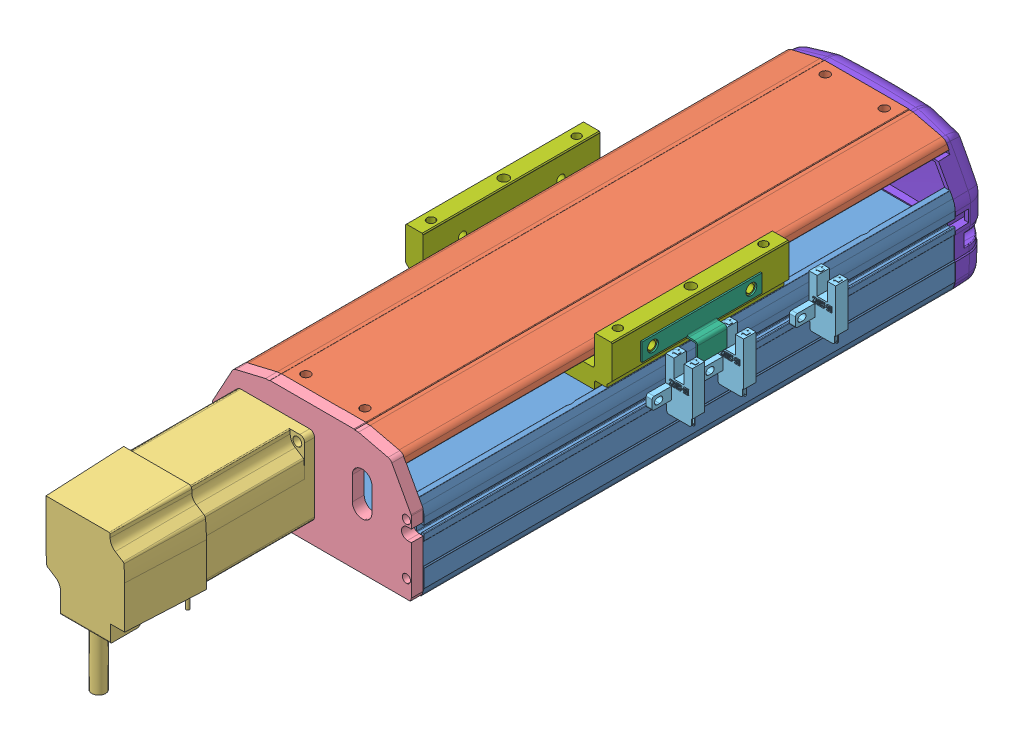
SolidWorks assembly S10-BC-100W, configuration 默认. Lengths in mm.
Overall size (117 93.4 393.51).
10 component instances, 8 part files, 32 mates.
Components (placement in the parent):
- S10-BC底座^S10-BC-100W-1: S10-BC底座^S10-BC-100W [默认] at origin size (102 43 282) (virtual)
- S10-BC上盖^S10-BC-100W-1: S10-BC上盖^S10-BC-100W [默认] at (0 59.5 144.1) size (83.88 8 276) (virtual)
-  M10^S10-BC-100W-1:  M10^S10-BC-100W [默认] at (-18.7 30.3 344) size (42.1 79.78 121.76) (virtual)
- S10-BC--P10电机板^S10-BC-100W-1: S10-BC--P10电机板^S10-BC-100W [Default] at (0 0 282) size (101 61.5 6) (virtual)
-  EE-SX672 传感器^S10-BC-100W-1:  EE-SX672 传感器^S10-BC-100W [默认] at (57.75 34.1 86.4) x (1 0 0) z (0 0 -1) size (13.5 27.4 26.1) (virtual)
- S10-GY外置感应钢片^S10-BC-100W-1: S10-GY外置感应钢片^S10-BC-100W [默认] at (52.9 60.5 143) size (6 19 61) (virtual)
-  EE-SX672 传感器^S10-BC-100W-2:  EE-SX672 传感器^S10-BC-100W [默认] at (57.75 34.1 133.1) x (1 0 0) z (0 0 -1) size (13.5 27.4 26.1) (virtual)
-  EE-SX672 传感器^S10-BC-100W-3:  EE-SX672 传感器^S10-BC-100W [默认] at (57.75 34.1 159.2) x (1 0 0) z (0 0 -1) size (13.5 27.4 26.1) (virtual)
- S10-BC滑座^S10-BC-100W-1: S10-BC滑座^S10-BC-100W [默认] at (-18.5 30.5 143) size (105 52.5 90) (virtual)
- S10端盖^S10-BC-100W-2: S10端盖^S10-BC-100W [默认] at (0.1 -1.5505 432.1) size (103.64 63.03 20.85) (virtual)
Mates (geometry in assembly coordinates):
- 重合23: coincident: plane of S10-BC底座^S10-BC-100W-1 through (-45.6042 41.8 282) normal (0 0 1); plane of S10-BC--P10电机板^S10-BC-100W-1 through (-37.9743 54.7457 282) normal (0 0 -1)
- 重合24: coincident: plane of S10-BC底座^S10-BC-100W-1 through (-24.5001 0 282) normal (0 -1 0); plane of S10-BC--P10电机板^S10-BC-100W-1 through (-49.9624 0 282) normal (0 -1 0)
- 重合25: coincident: plane of S10-BC底座^S10-BC-100W-1 through (-50.5 23.4167 282) normal (-1 0 0); plane of S10-BC--P10电机板^S10-BC-100W-1 through (-50.5 25.9995 282) normal (-1 0 0)
- 距离2: distance = 62.5 mm: plane of S10-BC上盖^S10-BC-100W-1 through (-21.3092 61.5 282.1) normal (0 1 0); plane of S10-BC底座^S10-BC-100W-1 through (0 -1 0) normal (0 -1 0)
- 重合31: coincident: plane of S10-BC底座^S10-BC-100W-1 through (0 0 0) normal (1 0 0); plane of S10-BC上盖^S10-BC-100W-1 through (0 59.5 144.1) normal (1 0 0)
- 距离3: distance = 66 mm: plane of S10-BC滑座^S10-BC-100W-1 through (-70.1396 65 72.2427) normal (0 1 0); plane of S10-BC底座^S10-BC-100W-1 through (0 -1 0) normal (0 -1 0)
- 距离5: distance = 1.5 mm: plane of S10-BC滑座^S10-BC-100W-1 through (52.5 45.0828 188) normal (1 0 0); plane of S10-BC底座^S10-BC-100W-1 through (51 3.0554 282) normal (1 0 0)
- 距离8: distance = 24 mm: plane of S10-BC底座^S10-BC-100W-1 through (0 -1 0) normal (0 -1 0); plane of  EE-SX672 传感器^S10-BC-100W-1 through (51 23 80.1) normal (0 -1 0)
- 重合59: coincident: plane of S10-BC底座^S10-BC-100W-1 through (51 24.0824 282) normal (1 0 0); plane of  EE-SX672 传感器^S10-BC-100W-1 through (51 45.2 80.1) normal (-1 0 0)
- 重合43: coincident: plane of S10-BC滑座^S10-BC-100W-1 through (52.5 45.0828 188) normal (1 0 0); plane of S10-GY外置感应钢片^S10-BC-100W-1 through (52.5 58.5 112.5) normal (-1 0 0)
- 重合51: coincident: plane of  EE-SX672 传感器^S10-BC-100W-1 through (51 45.2 80.1) normal (0 1 0); plane of  EE-SX672 传感器^S10-BC-100W-2 through (51 45.2 126.8) normal (0 1 0)
- 重合52: coincident: plane of  EE-SX672 传感器^S10-BC-100W-1 through (51 45.2 80.1) normal (0 1 0); plane of  EE-SX672 传感器^S10-BC-100W-3 through (51 45.2 152.9) normal (0 1 0)
- 重合56: coincident: plane of S10-BC--P10电机板^S10-BC-100W-1 through (-37.9743 54.7457 288) normal (0 0 1); plane of  M10^S10-BC-100W-1 through (59.2984 28.8022 288) normal (0 0 -1)
- 距离13: distance = 68 mm: plane of  EE-SX672 传感器^S10-BC-100W-1 through (64.5 23 80.1) normal (0 0 -1); plane of S10-BC底座^S10-BC-100W-1 through (46.75 42 12.1) normal (0 0 -1)
- 重合57: coincident: plane of  EE-SX672 传感器^S10-BC-100W-1 through (51 45.2 80.1) normal (-1 0 0); plane of  EE-SX672 传感器^S10-BC-100W-3 through (51 45.2 152.9) normal (-1 0 0)
- 重合58: coincident: plane of  EE-SX672 传感器^S10-BC-100W-2 through (51 45.2 126.8) normal (-1 0 0); plane of  EE-SX672 传感器^S10-BC-100W-3 through (51 45.2 152.9) normal (-1 0 0)
- 重合60: coincident: plane of  EE-SX672 传感器^S10-BC-100W-2 through (54 26.2 143) normal (0 0 1); plane of  EE-SX672 传感器^S10-BC-100W-3 through (54 26.2 143) normal (0 0 -1)
- 重合61: coincident: plane of S10-BC底座^S10-BC-100W-1 through (0 0 0) normal (1 0 0); plane of assembly through (0 0 0) normal (1 0 0)
- 重合62: coincident: plane of S10-BC底座^S10-BC-100W-1 through (0 0 0) normal (0 1 0); plane of assembly through (0 0 0) normal (0 1 0)
- 重合63: coincident: plane of S10-BC底座^S10-BC-100W-1 through (0 0 0) normal (0 0 1); plane of assembly through (0 0 0) normal (0 0 1)
- 重合65: coincident: plane of S10-BC底座^S10-BC-100W-1 through (46.75 42 12.1) normal (0 0 -1); plane of S10端盖^S10-BC-100W-2 through (-43.0846 34.4495 12.1) normal (0 0 1)
- 重合70: coincident: line of S10-BC底座^S10-BC-100W-1 through (47.4 31.8495 12.1) axis (1 0 0); line of S10端盖^S10-BC-100W-2 through (51.1 31.8495 12.1) axis (-1 0 0)
- 重合71: coincident: line of S10-BC底座^S10-BC-100W-1 through (47.1 26.4495 12.1) axis (0 1 0); line of S10端盖^S10-BC-100W-2 through (47.1 31.8495 12.1) axis (0 -1 0)
- 重合72: coincident: plane of S10-BC上盖^S10-BC-100W-1 through (-39.9297 53.7 6.1) normal (0 0 -1); plane of S10端盖^S10-BC-100W-2 through (50.1 51.9495 6.1) normal (0 0 1)
- 距离16: distance = 65.7 mm: cylinder of  M10^S10-BC-100W-1 through (-18.7 30.3 263) axis (0 0 1) radius 4; plane of S10-BC底座^S10-BC-100W-1 through (51 3.0554 282) normal (1 0 0)
- 距离17: distance = 27.3 mm: cylinder of  M10^S10-BC-100W-1 through (-18.7 30.3 263) axis (0 0 1) radius 4; plane of S10-BC底座^S10-BC-100W-1 through (0 -1 0) normal (0 -1 0)
- 平行2: parallel: plane of  M10^S10-BC-100W-1; plane of S10-BC--P10电机板^S10-BC-100W-1 through (-0.5 10 282) normal (0 1 0)
- 距离18: distance = 145 mm: plane of S10-BC--P10电机板^S10-BC-100W-1 through (-37.9743 54.7457 288) normal (0 0 1); cylinder of S10-BC滑座^S10-BC-100W-1 through (47.5 53 143) axis (0 1 0) radius 2.5
- 同心3: concentric: circle of S10-GY外置感应钢片^S10-BC-100W-1; cylinder of S10-BC滑座^S10-BC-100W-1 through (52.5 54 168) axis (1 0 0) radius 2.1
- 同心4: concentric: cylinder of S10-GY外置感应钢片^S10-BC-100W-1 through (52.5 54 118) axis (-1 0 0) radius 2.8; cylinder of S10-BC滑座^S10-BC-100W-1 through (52.5 54 118) axis (1 0 0) radius 2.1
- 宽度1: width: plane of  EE-SX672 传感器^S10-BC-100W-3 through (64.5 23 152.9) normal (0 0 -1); plane of  EE-SX672 传感器^S10-BC-100W-2 through (64.5 23 133.1) normal (0 0 1); plane of S10-GY外置感应钢片^S10-BC-100W-1 through (53.3 49.5 135.5) normal (0 0 -1); plane of S10-GY外置感应钢片^S10-BC-100W-1 through (53.3 49.5 150.5) normal (0 0 1)
- 平行4: parallel: plane of  M10^S10-BC-100W-1 through (1.3 50.3 288) normal (0 1 0); plane of S10-BC--P10电机板^S10-BC-100W-1 through (21.3105 61.5 282) normal (0 1 0)
